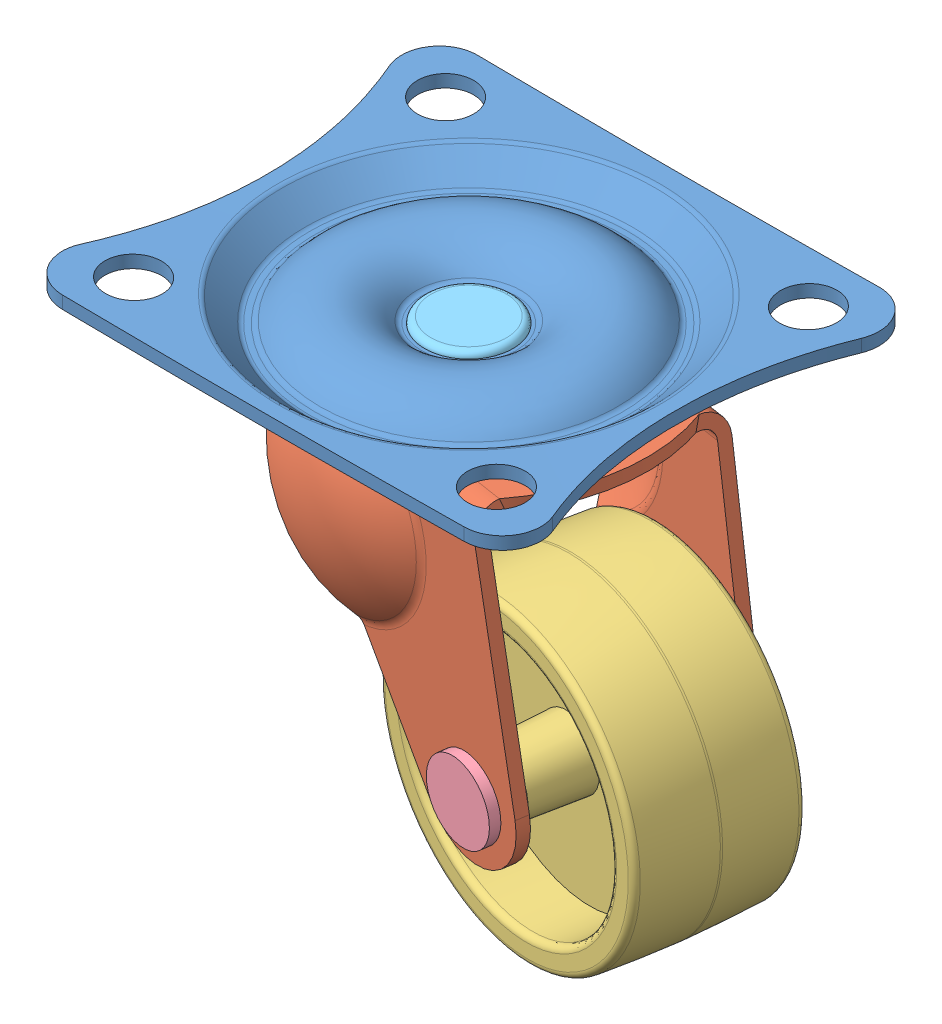
SolidWorks assembly Ensamble_Rueda_Loca, configuration Predeterminado. Lengths in mm.
Overall size (50.13 42.44 33).
5 component instances, 5 part files, 8 mates.
Components (placement in the parent):
- Base_rueda_loca-1: Base_rueda_loca [Predeterminado] at (0.7239 4.3377 41.0399) size (41.04 4 33)
- rueda loca-1: rueda loca [Predeterminado] at (0.7239 -3.6623 41.0399) x (0.15258 0 -0.988291) z (0.988291 0 0.15258) size (23.5 25.74 27.45)
- Llanta-1: Llanta [Predeterminado] at (12.3641 -17.7732 42.8347) x (0.152548 0.020285 -0.988088) z (0.775985 0.616686 0.132462) size (12.69 24.5 24.5)
- Eje_planta-1: Eje_planta [Predeterminado] at (10.931 -17.9637 52.1172) x (0.152548 0.020285 -0.988088) z (0.959429 -0.242914 0.143137) size (19.4 6 6)
- Pasante_Base-1: Pasante_Base [Predeterminado] at (0.7239 4.3377 41.0399) size (7 3 7)
Mates (geometry in assembly coordinates):
- Concéntrica1: concentric aligned: cylinder of Base_rueda_loca-1 through (0.7239 -5.6623 41.0399) axis (0 1 0) radius 2; cylinder of rueda loca-1 through (0.7239 -23.6623 41.0399) axis (0 1 0) radius 2
- Coincidente1: coincident aligned: circle of Base_rueda_loca-1; plane of rueda loca-1 through (0.7239 3.3377 41.0399) normal (0 1 0)
- Concéntrica2: concentric anti-aligned: cylinder of rueda loca-1 through (14.2212 -17.5262 30.8062) axis (-0.152548 -0.020285 0.988088) radius 1.5; cylinder of Llanta-1 through (11.3963 -17.9019 49.1035) axis (0.152548 0.020285 -0.988088) radius 1.75
- Distancia1: distance = 1.25 mm anti-aligned: plane of Llanta-1 through (9.8662 -15.9345 48.9077) normal (-0.152548 -0.020285 0.988088); plane of rueda loca-1 through (26.1871 2.263 53.0661) normal (0.152548 0.020285 -0.988088)
- Concéntrica3: concentric aligned: cylinder of rueda loca-1 through (14.2212 -17.5262 30.8062) axis (-0.152548 -0.020285 0.988088) radius 1.5; cylinder of Eje_planta-1 through (13.6921 -17.5966 34.2328) axis (-0.152548 -0.020285 0.988088) radius 1.5
- Coincidente2: coincident anti-aligned: plane of rueda loca-1 through (26.0345 2.2427 54.0542) normal (-0.152548 -0.020285 0.988088); plane of Eje_planta-1 through (11.0531 -17.9475 51.3267) normal (0.152548 0.020285 -0.988088)
- Coincidente3: coincident anti-aligned: plane of Base_rueda_loca-1 through (4.4877 4.3377 41.0399) normal (0 1 0); plane of Pasante_Base-1 through (0.7239 4.3377 41.0399) normal (0 -1 0)
- Concéntrica5: concentric aligned: cylinder of Base_rueda_loca-1 through (0.7239 -5.6623 41.0399) axis (0 1 0) radius 2; cylinder of Pasante_Base-1 through (0.7239 2.3377 41.0399) axis (0 1 0) radius 1.8229
